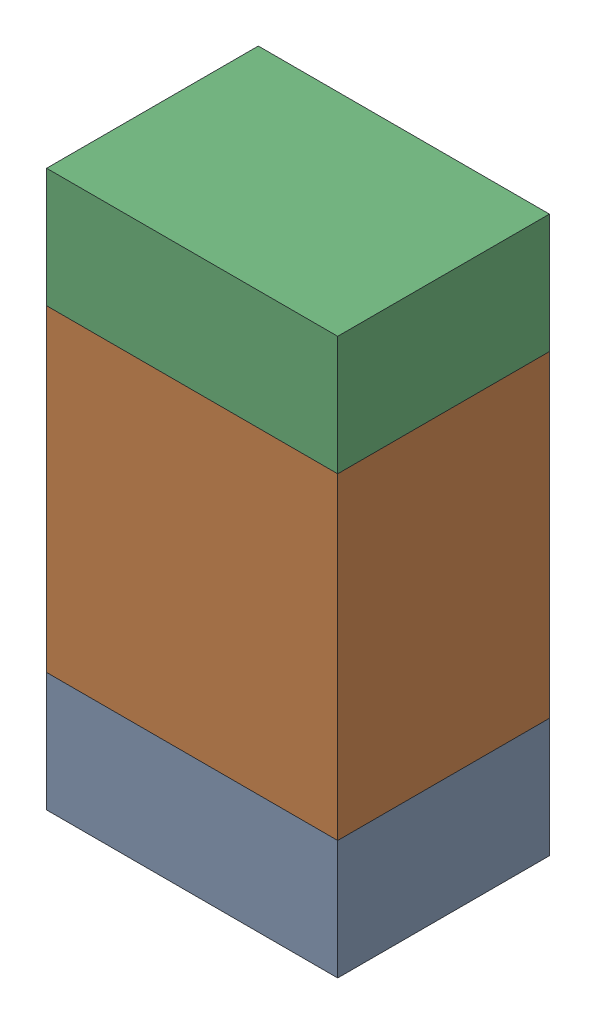
SolidWorks assembly R413PCB, configuration Default. Lengths in mm.
Overall size (0.55 1.05 0.4).
6 component instances, 2 part files, 0 mates.
Components (placement in the parent):
- 846483288-1: 846483288 [Default] at (123.4001 103.1876 -2.0638) size (0.55 0.22 0.4)
  - Extruded_12-1: Extruded_12 [Default] at origin size (0.55 0.22 0.4)
- 846483424-1: 846483424 [Default] at (123.4001 103.6001 -2.0638) size (0.55 0.6 0.4)
  - Extruded_13-1: Extruded_13 [Default] at origin size (0.55 0.6 0.4)
- 846483288-2: 846483288 [Default] at (123.4001 104.0126 -2.0638) size (0.55 0.22 0.4)
  - Extruded_12-1: Extruded_12 [Default] at origin size (0.55 0.22 0.4)
